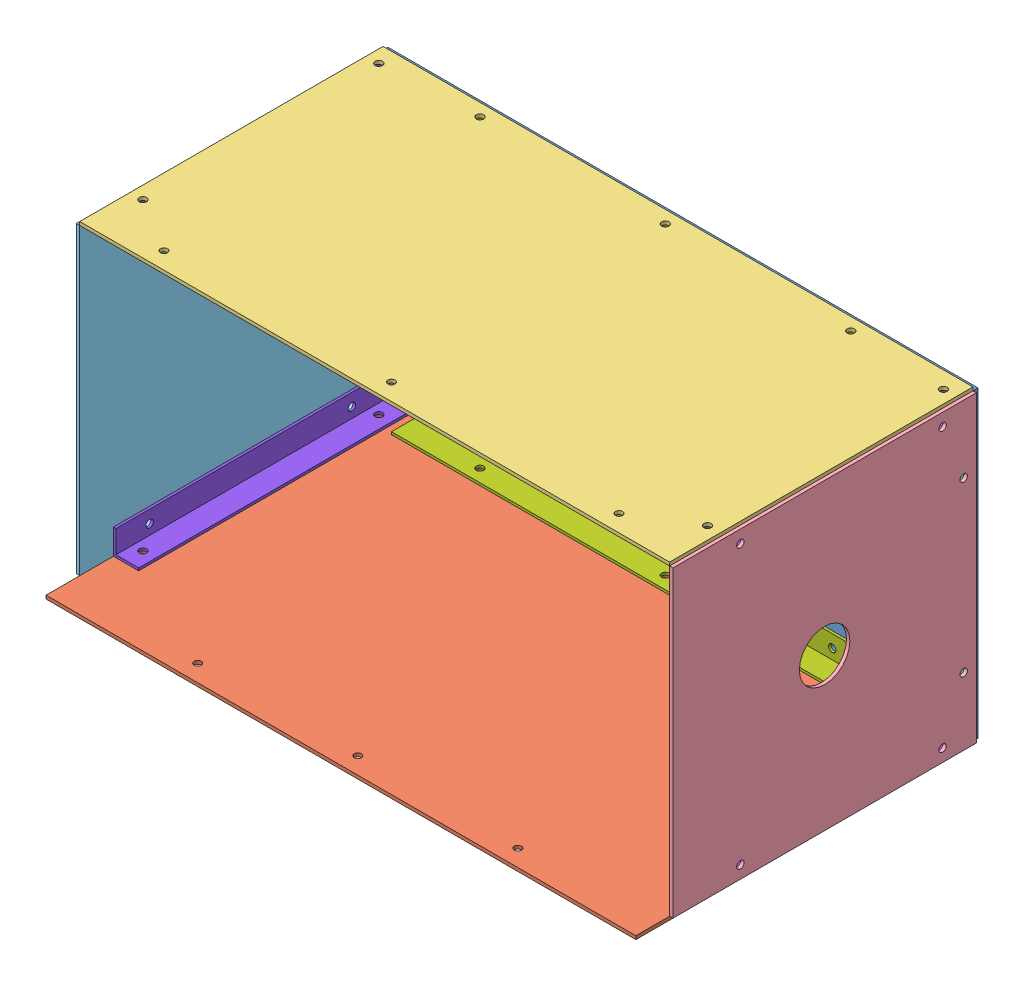
SolidWorks assembly PCケース, configuration ﾃﾞﾌｫﾙﾄ. Lengths in mm.
Overall size (354 184 203).
13 component instances, 8 part files, 32 mates.
Components (placement in the parent):
- PCケース下面-1: PCケース下面 [ﾃﾞﾌｫﾙﾄ] at (-2.2064 0.5516 348.5) size (350 180 3)
- PCケース右側面-1: PCケース右側面 [ﾃﾞﾌｫﾙﾄ] at (-2.2064 -91.4484 451.5) x (-1 0 0) z (0 1 0) size (350 200 2)
- PCケース左側面-1: PCケース左側面 [ﾃﾞﾌｫﾙﾄ] at (-2.2064 92.5516 441.5) x (1 0 0) z (0 -1 0) size (350 180 2)
- PCケース奥面-1: PCケース奥面 [ﾃﾞﾌｫﾙﾄ] at (174.7936 0.5516 441.5) x (0 -1 0) z (-1 0 0) size (180 180 2)
- PCケース正面-1: PCケース正面 [ﾃﾞﾌｫﾙﾄ] at (-179.2064 0.5516 441.5) x (0 1 0) z (1 0 0) size (180 180 2)
- 前後＆下面接続アングル-1: 前後＆下面接続アングル [ﾃﾞﾌｫﾙﾄ] at (172.7936 70.5516 351.5) x (0 0 1) z (0 -1 0) size (15 15 140)
- 前後＆下面接続アングル-2: 前後＆下面接続アングル [ﾃﾞﾌｫﾙﾄ] at (-177.2064 -69.4484 351.5) x (0 0 1) z (0 1 0) size (15 15 140)
- 左右&下面接続アングル-1: 左右&下面接続アングル [ﾃﾞﾌｫﾙﾄ] at (152.7936 -74.4484 351.5) x (0 0 1) z (-1 0 0) size (15 15 310)
- 左右&下面接続アングル-2: 左右&下面接続アングル [ﾃﾞﾌｫﾙﾄ] at (-157.2064 75.5516 351.5) x (0 0 1) z (1 0 0) size (15 15 310)
- 縦方向接続アングル-1: 縦方向接続アングル [ﾃﾞﾌｫﾙﾄ] at (172.7936 -89.4484 511.5) x (-1 0 0) z (0 0 -1) size (15 15 160)
- 縦方向接続アングル-2: 縦方向接続アングル [ﾃﾞﾌｫﾙﾄ] at (-177.2064 -89.4484 351.5) size (15 15 160)
- 縦方向接続アングル-3: 縦方向接続アングル [ﾃﾞﾌｫﾙﾄ] at (-177.2064 90.5516 511.5) x (1 0 0) z (0 0 -1) size (15 15 160)
- 縦方向接続アングル-4: 縦方向接続アングル [ﾃﾞﾌｫﾙﾄ] at (172.7936 90.5516 351.5) x (-1 0 0) z (0 0 1) size (15 15 160)
Mates (geometry in assembly coordinates):
- 一致10: coincident: line of PCケース下面-1 through (-177.2064 -89.4484 351.5) axis (1 0 0); line of PCケース右側面-1 through (172.7936 -89.4484 351.5) axis (-1 0 0)
- 一致12: coincident: line of PCケース下面-1 through (172.7936 90.5516 351.5) axis (-1 0 0); line of PCケース左側面-1 through (-177.2064 90.5516 351.5) axis (1 0 0)
- 同心円1: concentric: cylinder of PCケース下面-1 through (165.2936 60.5516 211.5) axis (0 0 1) radius 2.2; cylinder of 前後＆下面接続アングル-1 through (165.2936 60.5516 491.5) axis (0 0 -1) radius 2.1
- 同心円2: concentric: cylinder of PCケース下面-1 through (165.2936 -59.4484 211.5) axis (0 0 1) radius 2.2; cylinder of 前後＆下面接続アングル-1 through (165.2936 -59.4484 491.5) axis (0 0 -1) radius 2.1
- 一致14: coincident: plane of PCケース下面-1 through (-2.2064 0.5516 351.5) normal (0 0 1); plane of 前後＆下面接続アングル-1 through (172.7936 -69.4484 351.5) normal (0 0 -1)
- 同心円3: concentric: cylinder of PCケース下面-1 through (-169.7064 -59.4484 211.5) axis (0 0 1) radius 2.2; cylinder of 前後＆下面接続アングル-2 through (-169.7064 -59.4484 491.5) axis (0 0 -1) radius 2.1
- 同心円4: concentric: cylinder of PCケース下面-1 through (-169.7064 60.5516 211.5) axis (0 0 1) radius 2.2; cylinder of 前後＆下面接続アングル-2 through (-169.7064 60.5516 491.5) axis (0 0 -1) radius 2.1
- 一致15: coincident: plane of PCケース下面-1 through (-2.2064 0.5516 351.5) normal (0 0 1); plane of 前後＆下面接続アングル-2 through (-177.2064 70.5516 351.5) normal (0 0 -1)
- 一致16: coincident: circle of PCケース奥面-1; cylinder of 前後＆下面接続アングル-1 through (32.7936 50.5516 359) axis (1 0 0) radius 2.2
- 一致17: coincident: cylinder of PCケース奥面-1 through (172.7936 -49.4484 359) axis (1 0 0) radius 2.2; circle of 前後＆下面接続アングル-1
- 一致18: coincident: line of PCケース右側面-1 through (172.7936 -89.4484 551.5) axis (0 0 -1); line of PCケース奥面-1 through (172.7936 -89.4484 351.5) axis (0 0 1)
- 同心円5: concentric: cylinder of PCケース正面-1 through (-317.2064 50.5516 359) axis (1 0 0) radius 2.2; cylinder of 前後＆下面接続アングル-2 through (-37.2064 50.5516 359) axis (-1 0 0) radius 2.2
- 同心円6: concentric: cylinder of PCケース正面-1 through (-317.2064 -49.4484 359) axis (1 0 0) radius 2.2; cylinder of 前後＆下面接続アングル-2 through (-37.2064 -49.4484 359) axis (-1 0 0) radius 2.2
- 一致19: coincident: plane of PCケース正面-1 through (-177.2064 0.5516 441.5) normal (1 0 0); plane of 前後＆下面接続アングル-2 through (-177.2064 70.5516 366.5) normal (-1 0 0)
- 一致20: coincident: plane of PCケース奥面-1 through (172.7936 0.5516 441.5) normal (-1 0 0); plane of 前後＆下面接続アングル-1 through (172.7936 -69.4484 366.5) normal (1 0 0)
- 同心円7: concentric: cylinder of PCケース下面-1 through (90.7936 -81.9484 41.5) axis (0 0 1) radius 2.2; cylinder of 左右&下面接続アングル-1 through (90.7936 -81.9484 661.5) axis (0 0 -1) radius 2.2
- 同心円8: concentric: cylinder of PCケース下面-1 through (-95.2064 -81.9484 41.5) axis (0 0 1) radius 2.2; cylinder of 左右&下面接続アングル-1 through (-95.2064 -81.9484 661.5) axis (0 0 -1) radius 2.2
- 一致21: coincident: plane of PCケース下面-1 through (-2.2064 0.5516 351.5) normal (0 0 1); plane of 左右&下面接続アングル-1 through (-157.2064 -74.4484 351.5) normal (0 0 -1)
- 一致22: coincident: plane of PCケース右側面-1 through (-2.2064 -89.4484 451.5) normal (0 1 0); plane of 左右&下面接続アングル-1 through (-157.2064 -89.4484 351.5) normal (0 -1 0)
- 同心円9: concentric: cylinder of PCケース下面-1 through (90.7936 83.0516 41.5) axis (0 0 1) radius 2.2; cylinder of 左右&下面接続アングル-2 through (90.7936 83.0516 661.5) axis (0 0 -1) radius 2.2
- 同心円10: concentric: cylinder of PCケース下面-1 through (-95.2064 83.0516 41.5) axis (0 0 1) radius 2.2; cylinder of 左右&下面接続アングル-2 through (-95.2064 83.0516 661.5) axis (0 0 -1) radius 2.2
- 一致23: coincident: plane of PCケース下面-1 through (-2.2064 0.5516 351.5) normal (0 0 1); plane of 左右&下面接続アングル-2 through (152.7936 75.5516 351.5) normal (0 0 -1)
- 同心円11: concentric: cylinder of PCケース右側面-1 through (165.2936 -249.4484 501.5) axis (0 1 0) radius 2.2; cylinder of 縦方向接続アングル-1 through (165.2936 70.5516 501.5) axis (0 -1 0) radius 2.2
- 同心円12: concentric: cylinder of PCケース右側面-1 through (165.2936 -249.4484 361.5) axis (0 1 0) radius 2.2; cylinder of 縦方向接続アングル-1 through (165.2936 70.5516 361.5) axis (0 -1 0) radius 2.2
- 一致24: coincident: plane of PCケース右側面-1 through (-2.2064 -89.4484 451.5) normal (0 1 0); plane of 縦方向接続アングル-1 through (157.7936 -89.4484 351.5) normal (0 -1 0)
- 同心円13: concentric: cylinder of PCケース右側面-1 through (-169.7064 -249.4484 501.5) axis (0 1 0) radius 2.2; cylinder of 縦方向接続アングル-2 through (-169.7064 70.5516 501.5) axis (0 -1 0) radius 2.2
- 同心円14: concentric: cylinder of PCケース正面-1 through (-337.2064 -81.9484 371.5) axis (1 0 0) radius 2.2; cylinder of 縦方向接続アングル-2 through (-162.2064 -81.9484 371.5) axis (-1 0 0) radius 2.2
- 同心円15: concentric: cylinder of PCケース左側面-1 through (-169.7064 250.5516 361.5) axis (0 -1 0) radius 2.2; cylinder of 縦方向接続アングル-3 through (-169.7064 -69.4484 361.5) axis (0 1 0) radius 2.2
- 同心円16: concentric: cylinder of PCケース正面-1 through (-337.2064 83.0516 371.5) axis (1 0 0) radius 2.2; cylinder of 縦方向接続アングル-3 through (-162.2064 83.0516 371.5) axis (-1 0 0) radius 2.2
- 同心円17: concentric: cylinder of PCケース左側面-1 through (165.2936 250.5516 361.5) axis (0 -1 0) radius 2.2; cylinder of 縦方向接続アングル-4 through (165.2936 -69.4484 361.5) axis (0 1 0) radius 2.2
- 一致25: coincident: cylinder of PCケース奥面-1 through (14.7936 83.0516 491.5) axis (1 0 0) radius 2.2; circle of 縦方向接続アングル-4
- 一致26: coincident: plane of PCケース奥面-1 through (172.7936 0.5516 441.5) normal (-1 0 0); plane of 縦方向接続アングル-4 through (172.7936 90.5516 511.5) normal (1 0 0)
